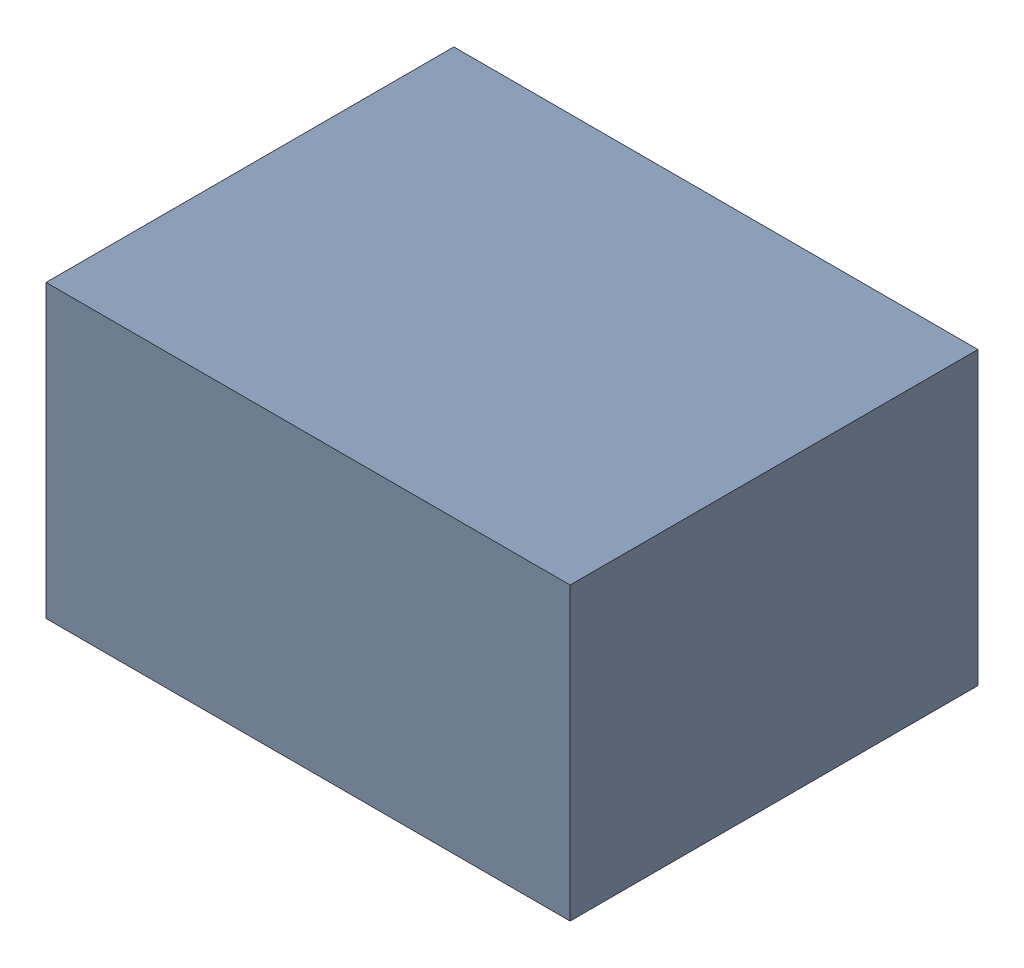
SolidWorks assembly C1, configuration Default. Lengths in mm.
Overall size (1.8 1 1.4).
3 component instances, 2 part files, 0 mates.
Components (placement in the parent):
- 1088884976-1: 1088884976 [Default] at (12.775 42.175 0) size (1.8 1 1.4)
  - Extruded-47-1: Extruded-47 [Default] at origin size (1.8 1 1.4)
- C0603-1: C0603 [Default] at (13.5751 42.5751 0) x (-1 0 0) z (0 1 0) size (1.6 0.5 0.8)
